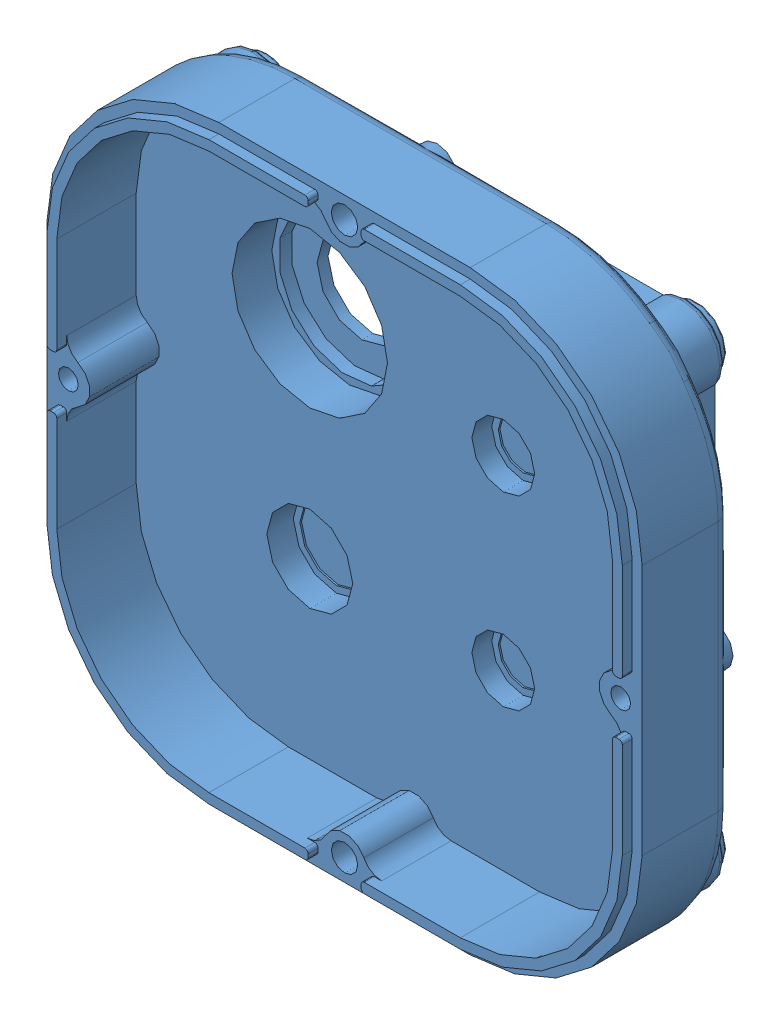
SolidWorks assembly Assemblage2, configuration Défaut. Lengths in mm.
Overall size (180 180 44.8).
6 component instances, 2 part files, 10 mates.
Components (placement in the parent):
- Carter superieur reducteur-1: Carter superieur reducteur [Défaut] at origin size (180 180 44.8)
- Insert metallique avec collerette-1: Insert metallique avec collerette [Défaut] at (-65 65 -14.8) x (-0.804364 -0.594137 0) z (0.594137 -0.804364 0) size (12 15 12)
- Insert metallique avec collerette-2: Insert metallique avec collerette [Défaut] at (65 65 -14.8) x (-0.432861 -0.901461 0) z (0.901461 -0.432861 0) size (12 15 12)
- Insert metallique avec collerette-3: Insert metallique avec collerette [Défaut] at (-65 -65 -14.8) x (-0.432861 -0.901461 0) z (0.901461 -0.432861 0) size (12 15 12)
- Insert metallique avec collerette-4: Insert metallique avec collerette [Défaut] at (65 -65 -14.8) x (0.248467 -0.96864 0) z (0.96864 0.248467 0) size (12 15 12)
- Insert metallique avec collerette-5: Insert metallique avec collerette [Défaut] at (0 0 -14.8) x (-0.934662 -0.355538 0) z (0.355538 -0.934662 0) size (12 15 12)
Mates (geometry in assembly coordinates):
- Coaxiale1: concentric: cylinder of Carter superieur reducteur-1 through (-65 65 -13.3) axis (0 0 -1) radius 5; cylinder of Insert metallique avec collerette-1 through (-65 65 -17.8) axis (0 0 -1) radius 5
- Coïncidente1: coincident anti-aligned: plane of Carter superieur reducteur-1 through (-65 65 -13.3) normal (0 0 -1); plane of Insert metallique avec collerette-1 through (-69.8262 61.4352 -13.3) normal (0 0 1)
- Coaxiale2: concentric: cylinder of Carter superieur reducteur-1 through (65 65 -13.3) axis (0 0 -1) radius 5; cylinder of Insert metallique avec collerette-2 through (65 65 -17.8) axis (0 0 -1) radius 5
- Coïncidente2: coincident anti-aligned: plane of Carter superieur reducteur-1 through (65 65 -13.3) normal (0 0 -1); plane of Insert metallique avec collerette-2 through (62.4028 59.5912 -13.3) normal (0 0 1)
- Coaxiale3: concentric: cylinder of Carter superieur reducteur-1 through (65 -65 -13.3) axis (0 0 -1) radius 5; cylinder of Insert metallique avec collerette-4 through (65 -65 -17.8) axis (0 0 -1) radius 5
- Coïncidente3: coincident anti-aligned: plane of Carter superieur reducteur-1 through (65 -65 -13.3) normal (0 0 -1); plane of Insert metallique avec collerette-4 through (66.4908 -70.8118 -13.3) normal (0 0 1)
- Coaxiale4: concentric: cylinder of Carter superieur reducteur-1 through (-65 -65 -13.3) axis (0 0 -1) radius 5; cylinder of Insert metallique avec collerette-3 through (-65 -65 -17.8) axis (0 0 -1) radius 5
- Coïncidente4: coincident anti-aligned: plane of Carter superieur reducteur-1 through (-65 -65 -13.3) normal (0 0 -1); plane of Insert metallique avec collerette-3 through (-67.5972 -70.4088 -13.3) normal (0 0 1)
- Coaxiale5: concentric: cylinder of Carter superieur reducteur-1 through (0 0 -13.3) axis (0 0 -1) radius 5; cylinder of Insert metallique avec collerette-5 through (0 0 -80.9831) axis (0 0 -1) radius 5
- Coïncidente5: coincident anti-aligned: plane of Carter superieur reducteur-1 through (0 0 -13.3) normal (0 0 -1); plane of Insert metallique avec collerette-5 through (-5.608 -2.1332 -13.3) normal (0 0 1)
